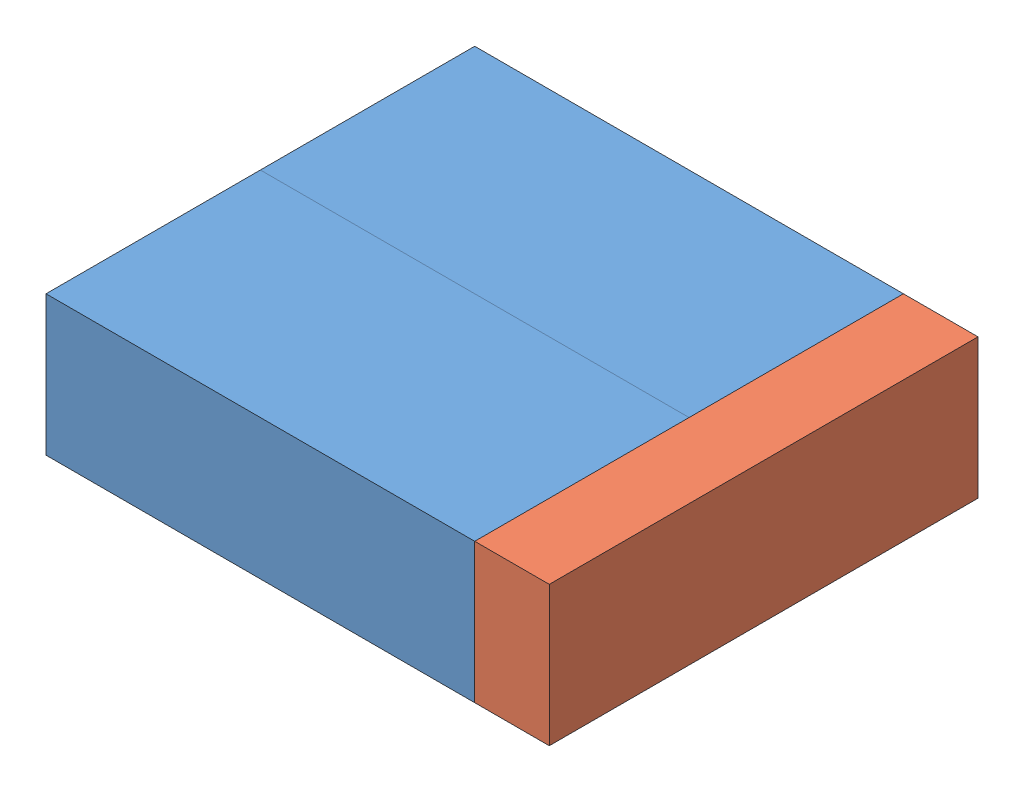
SolidWorks assembly Assem1, configuration Default. Lengths in mm.
Overall size (270 75 230).
3 component instances, 2 part files, 5 mates.
Components (placement in the parent):
- Brick-Whole-1: Brick-Whole [Default] at (83.535 127.3211 172.812) size (230 75 115)
- Brick-Whole-2: Brick-Whole [Default] at (83.535 127.3211 287.812) size (230 75 115)
- Brick-Whole-trimmed-1: Brick-Whole-trimmed [Default] at (218.535 127.3211 230.312) x (0 0 1) z (-1 0 0) size (230 75 40)
Mates (geometry in assembly coordinates):
- Coincident1: coincident: plane of Brick-Whole-1 through (-31.465 164.8211 230.312) normal (0 0 1); plane of Brick-Whole-2 through (-90.6864 164.8211 230.312) normal (0 0 -1)
- Coincident2: coincident: line of Brick-Whole-1 through (-31.465 89.8211 230.312) axis (1 0 0); line of Brick-Whole-2 through (139.3136 89.8211 230.312) axis (-1 0 0)
- Coincident3: coincident aligned: line of Brick-Whole-1 through (198.535 164.8211 230.312) axis (0 -1 0); line of Brick-Whole-2 through (198.535 164.8211 230.312) axis (0 -1 0)
- Coincident4: coincident: plane of Brick-Whole-1 through (198.535 164.8211 115.312) normal (1 0 0); plane of Brick-Whole-trimmed-1 through (198.535 164.8211 115.312) normal (-1 0 0)
- Coincident5: coincident aligned: line of Brick-Whole-2 through (-31.465 89.8211 345.312) axis (1 0 0); line of Brick-Whole-trimmed-1 through (198.535 89.8211 345.312) axis (1 0 0)
